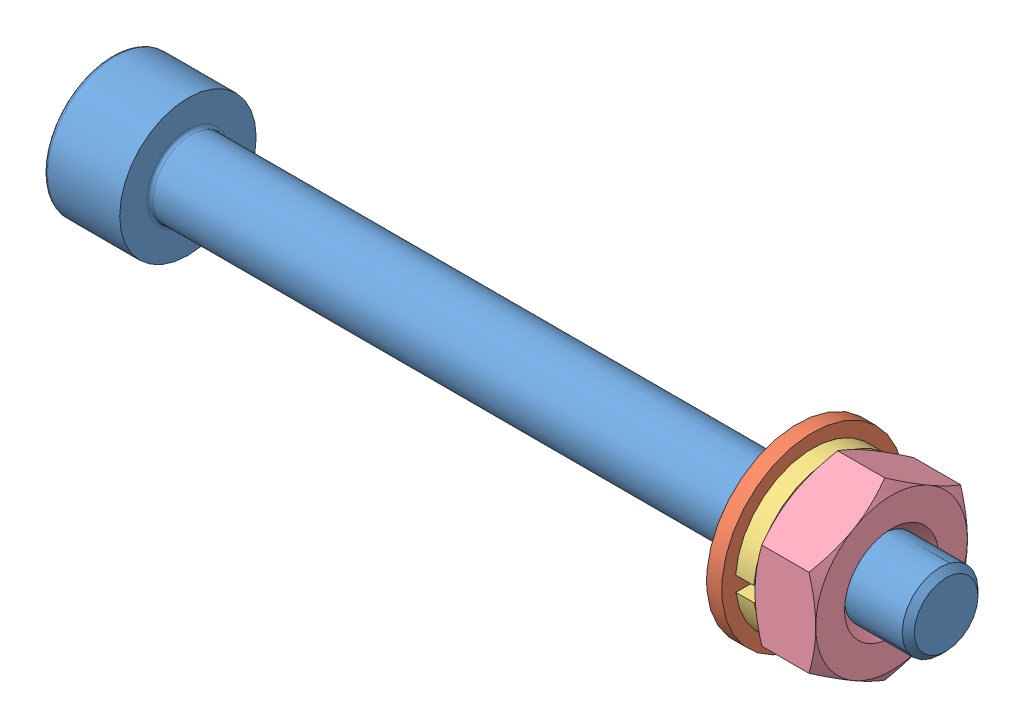
SolidWorks assembly SCREWS_ASSM_4, configuration Default. Lengths in mm.
Overall size (27.5 6 6).
4 component instances, 4 part files, 6 mates.
Components (placement in the parent):
- DIN_912_M2.5_25H-1: DIN_912_M2.5_25H [По умолчанию] at origin size (27.5 4.5 4.5)
- DIN_125_M2.5_WASHER_NORMAL-1: DIN_125_M2.5_WASHER_NORMAL [Default] at (23.1 0 0) x (0 0 1) z (-1 0 0) size (6 6 0.5)
- DIN_127_M2.5_SPRING_WASHER-1: DIN_127_M2.5_SPRING_WASHER [Default] at (23.7 0 0) x (0 0 1) z (-1 0 0) size (5.09 5.1 0.6)
- DIN_934_M2.5_HEX_NUT-1: DIN_934_M2.5_HEX_NUT [По умолчанию] at (25.7 0 0) x (0 0 1) z (-1 0 0) size (5 5.77 2)
Mates (geometry in assembly coordinates):
- Concentric1: concentric anti-aligned: cylinder of DIN_912_M2.5_25H-1 through (0 0 0) axis (-1 0 0) radius 1.25; cylinder of DIN_125_M2.5_WASHER_NORMAL-1 through (23 0 0) axis (1 0 0) radius 1.35
- Concentric2: concentric anti-aligned: cylinder of DIN_912_M2.5_25H-1 through (0 0 0) axis (-1 0 0) radius 1.25; cylinder of DIN_127_M2.5_SPRING_WASHER-1 through (23.5 0 0) axis (1 0 0) radius 1.45
- Concentric3: concentric anti-aligned: cylinder of DIN_912_M2.5_25H-1 through (0 0 0) axis (-1 0 0) radius 1.25; cylinder of DIN_934_M2.5_HEX_NUT-1 through (24.1 0 0) axis (1 0 0) radius 1.25
- Coincident1: coincident anti-aligned: plane of DIN_125_M2.5_WASHER_NORMAL-1 through (23.5 0 0) normal (1 0 0); plane of DIN_127_M2.5_SPRING_WASHER-1 through (23.5 0 0) normal (-1 0 0)
- Coincident2: coincident anti-aligned: plane of DIN_127_M2.5_SPRING_WASHER-1 through (24.1 0 0) normal (1 0 0); plane of DIN_934_M2.5_HEX_NUT-1 through (24.1 0 0) normal (-1 0 0)
- Distance1: distance = 20.1 mm anti-aligned: plane of DIN_125_M2.5_WASHER_NORMAL-1 through (22.6 0 0) normal (-1 0 0); plane of DIN_912_M2.5_25H-1 through (2.5 0 0) normal (1 0 0)
